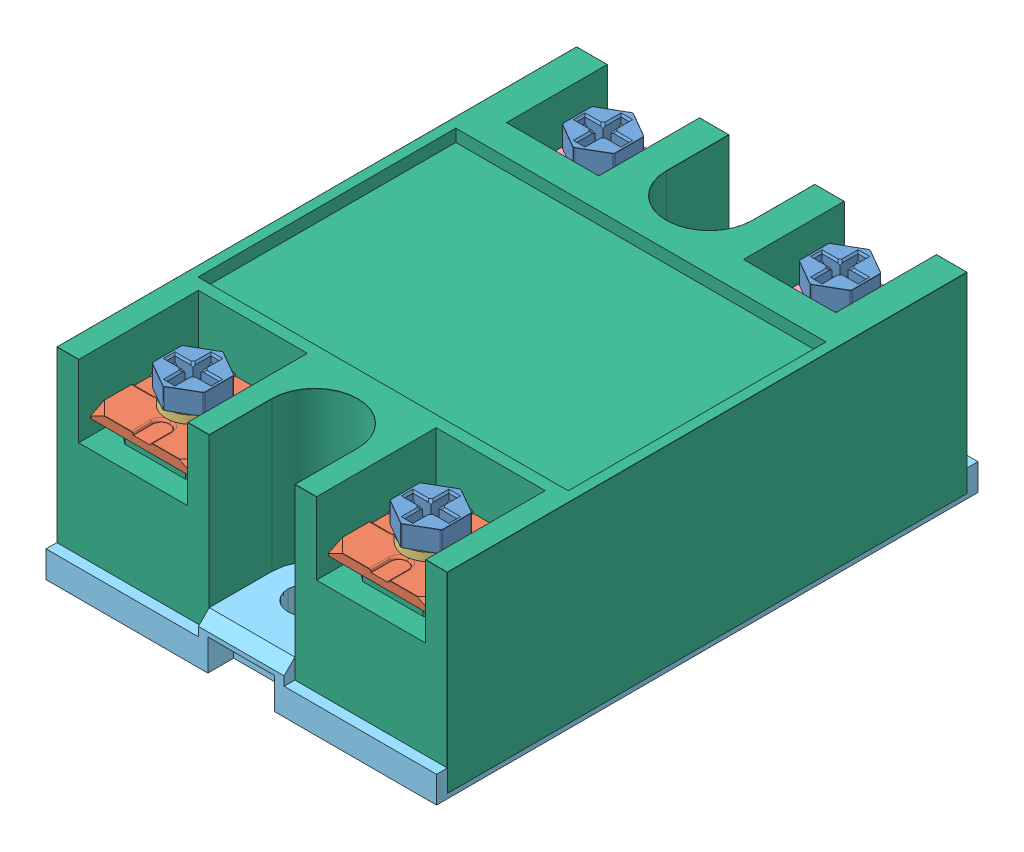
SolidWorks assembly SSR-40 DA, configuration Défaut. Lengths in mm.
Overall size (44.93 22.58 62.31).
20 component instances, 6 part files, 0 mates.
Components (placement in the parent):
- SSR-40 DA.STEP-1: SSR-40 DA.STEP [Défaut] at origin size (44.93 22.58 62.31)
  - SSR-40 DA.iam.STEP-1: SSR-40 DA.iam.STEP [Défaut] at origin size (44.93 22.58 62.31)
    - SSR-40 DA Large P W S.iam.STEP-1: SSR-40 DA Large P W S.iam.STEP [Défaut] at (16.3314 5.9081 19.4506) size (11.79 12.32 11.79)
      - SSR-40 DA Screw.ipt.STEP-1: SSR-40 DA Screw.ipt.STEP [Défaut] at (-7.6255 -5.9657 0.3915) size (5.98 12.32 6.83)
      - SSR-40 DA Big Plate.ipt.STEP-1: SSR-40 DA Big Plate.ipt.STEP [Défaut] at (-7.6255 1.407 0.3915) size (11.79 1.07 11.79)
      - SSR-40 DA Lock Washer.ipt.STEP-1: SSR-40 DA Lock Washer.ipt.STEP [Défaut] at (-7.6255 2.9611 0.3915) x (0.999998 0 -0.001876) z (0.001876 0 0.999998) size (6.05 1.45 6.13)
    - SSR-40 DA Large P W S.iam.STEP-2: SSR-40 DA Large P W S.iam.STEP [Défaut] at (-11.0371 5.9081 19.4506) size (11.79 12.32 11.79)
      - SSR-40 DA Screw.ipt.STEP-1: SSR-40 DA Screw.ipt.STEP [Défaut] at (-7.6255 -5.9657 0.3915) size (5.98 12.32 6.83)
      - SSR-40 DA Big Plate.ipt.STEP-1: SSR-40 DA Big Plate.ipt.STEP [Défaut] at (-7.6255 1.407 0.3915) size (11.79 1.07 11.79)
      - SSR-40 DA Lock Washer.ipt.STEP-1: SSR-40 DA Lock Washer.ipt.STEP [Défaut] at (-7.6255 2.9611 0.3915) x (0.999998 0 -0.001876) z (0.001876 0 0.999998) size (6.05 1.45 6.13)
    - SSR-40 DA Small P W S.iam.STEP-1: SSR-40 DA Small P W S.iam.STEP [Défaut] at (-10.9863 6.176 -27.5619) size (9.73 12.32 9.73)
      - SSR-40 DA Screw.ipt.STEP-1: SSR-40 DA Screw.ipt.STEP [Défaut] at (-7.6255 -5.9657 0.2744) size (5.98 12.32 6.83)
      - SSR-40 DA Lock Washer.ipt.STEP-1: SSR-40 DA Lock Washer.ipt.STEP [Défaut] at (-7.6255 2.9611 0.2744) x (0.999998 0 -0.001876) z (0.001876 0 0.999998) size (6.05 1.45 6.13)
      - SSR-40 DA Small Plate.ipt.STEP-1: SSR-40 DA Small Plate.ipt.STEP [Défaut] at (-7.6255 1.3677 0.2744) size (9.73 1.07 9.73)
    - SSR-40 DA Small P W S.iam.STEP-2: SSR-40 DA Small P W S.iam.STEP [Défaut] at (16.2806 6.176 -27.5619) size (9.73 12.32 9.73)
      - SSR-40 DA Screw.ipt.STEP-1: SSR-40 DA Screw.ipt.STEP [Défaut] at (-7.6255 -5.9657 0.2744) size (5.98 12.32 6.83)
      - SSR-40 DA Lock Washer.ipt.STEP-1: SSR-40 DA Lock Washer.ipt.STEP [Défaut] at (-7.6255 2.9611 0.2744) x (0.999998 0 -0.001876) z (0.001876 0 0.999998) size (6.05 1.45 6.13)
      - SSR-40 DA Small Plate.ipt.STEP-1: SSR-40 DA Small Plate.ipt.STEP [Défaut] at (-7.6255 1.3677 0.2744) size (9.73 1.07 9.73)
    - SSR-40 DA BOTTOM.ipt.STEP-1: SSR-40 DA BOTTOM.ipt.STEP [Défaut] at (-4.9847 -9.068 -3.183) size (44.93 5.36 62.31)
    - SSR-40 DA TOP.ipt.STEP-1: SSR-40 DA TOP.ipt.STEP [Défaut] at (-4.9847 -8.5346 -3.183) size (44.93 22.05 59.82)
